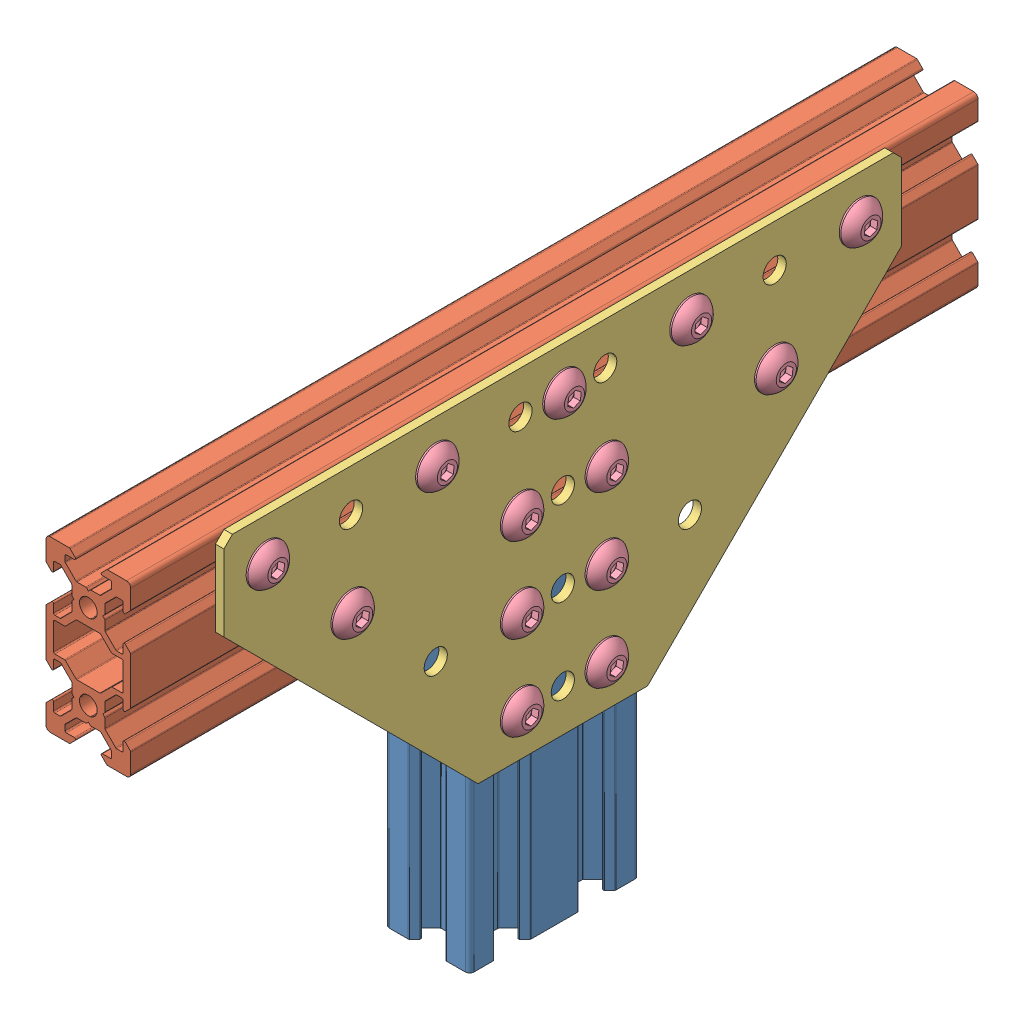
SolidWorks assembly Т-пластина 20 серия унив. 22отв  80х160х2 СБ, configuration По умолчанию. Lengths in mm.
Overall size (24.75 120 200).
16 component instances, 4 part files, 35 mates.
Components (placement in the parent):
- 204090-1: 204090 [По умолчанию] at (-10 0 -10) x (0 0 -1) z (0 1 0) size (40 20 80)
- 2040120-1: 2040120 [По умолчанию] at (-10 110 -120) x (0 -1 0) z (0 0 1) size (40 20 200)
- Т-пластина 20 серия унив. 22отв  80х160х2-1: Т-пластина 20 серия унив. 22отв  80х160х2 [По умолчанию] at (2 40 -20) x (0 0 -1) z (1 0 0) size (160 80 2)
- socket button head screw_iso-13: socket button head screw_iso [ISO 7380 - M5 x 10 - 10N] at (4.75 110 50) x (-1 0 0) z (0 0.924225 0.381849) size (12.75 9.5 9.5)
- socket button head screw_iso-14: socket button head screw_iso [ISO 7380 - M5 x 10 - 10N] at (4.75 90 30) x (-1 0 0) z (0 0.924225 0.381849) size (12.75 9.5 9.5)
- socket button head screw_iso-15: socket button head screw_iso [ISO 7380 - M5 x 10 - 10N] at (4.75 110 10) x (-1 0 0) z (0 0.924225 0.381849) size (12.75 9.5 9.5)
- socket button head screw_iso-16: socket button head screw_iso [ISO 7380 - M5 x 10 - 10N] at (4.75 110 -20) x (-1 0 0) z (0 0.924225 0.381849) size (12.75 9.5 9.5)
- socket button head screw_iso-17: socket button head screw_iso [ISO 7380 - M5 x 10 - 10N] at (4.75 110 -90) x (-1 0 0) z (0 0.924225 0.381849) size (12.75 9.5 9.5)
- socket button head screw_iso-18: socket button head screw_iso [ISO 7380 - M5 x 10 - 10N] at (4.75 110 -50) x (-1 0 0) z (0 0.924225 0.381849) size (12.75 9.5 9.5)
- socket button head screw_iso-19: socket button head screw_iso [ISO 7380 - M5 x 10 - 10N] at (4.75 90 -70) x (-1 0 0) z (0 0.924225 0.381849) size (12.75 9.5 9.5)
- socket button head screw_iso-20: socket button head screw_iso [ISO 7380 - M5 x 10 - 10N] at (4.75 90 -30) x (-1 0 0) z (0 0.924225 0.381849) size (12.75 9.5 9.5)
- socket button head screw_iso-21: socket button head screw_iso [ISO 7380 - M5 x 10 - 10N] at (4.75 90 -10) x (-1 0 0) z (0 0.924225 0.381849) size (12.75 9.5 9.5)
- socket button head screw_iso-22: socket button head screw_iso [ISO 7380 - M5 x 10 - 10N] at (4.75 50 -10) x (-1 0 0) z (0 0.924225 0.381849) size (12.75 9.5 9.5)
- socket button head screw_iso-23: socket button head screw_iso [ISO 7380 - M5 x 10 - 10N] at (4.75 70 -10) x (-1 0 0) z (0 0.924225 0.381849) size (12.75 9.5 9.5)
- socket button head screw_iso-24: socket button head screw_iso [ISO 7380 - M5 x 10 - 10N] at (4.75 70 -30) x (-1 0 0) z (0 0.924225 0.381849) size (12.75 9.5 9.5)
- socket button head screw_iso-25: socket button head screw_iso [ISO 7380 - M5 x 10 - 10N] at (4.75 50 -30) x (-1 0 0) z (0 0.924225 0.381849) size (12.75 9.5 9.5)
Mates (geometry in assembly coordinates):
- Совпадение1: coincident anti-aligned: plane of 204090-1 through (-10 0 -10) normal (0 -1 0)
- Совпадение2: coincident aligned: plane of 204090-1 through (0 80 -25.6) normal (1 0 0)
- Совпадение3: coincident aligned: plane of 204090-1 through (-20 80 0) normal (0 0 1)
- Совпадение4: coincident anti-aligned: plane of 204090-1 through (-10 80 -10) normal (0 1 0); plane of 2040120-1 through (-20 80 80) normal (0 -1 0)
- Совпадение5: coincident aligned: plane of 204090-1 through (0 80 -25.6) normal (1 0 0); plane of 2040120-1 through (0 80 80) normal (1 0 0)
- Совпадение6: coincident anti-aligned: plane of 2040120-1 through (0 94.4 80) normal (1 0 0); plane of Т-пластина 20 серия унив. 22отв  80х160х2-1 through (0 40 -20) normal (-1 0 0)
- Совпадение7: coincident aligned: plane of 2040120-1 through (0 120 80) normal (0 1 0); plane of Т-пластина 20 серия унив. 22отв  80х160х2-1 through (0 120 -20) normal (0 1 0)
- Расстояние1: distance = 20 mm aligned: plane of 2040120-1 through (-10 110 80) normal (0 0 1); plane of Т-пластина 20 серия унив. 22отв  80х160х2-1 through (0 120 60) normal (0 0 1)
- Совпадение9: coincident: plane of 204090-1 through (0 80 0) normal (0 0 1); line of Т-пластина 20 серия унив. 22отв  80х160х2-1 through (0 40 0) axis (1 0 0)
- Концентричный1: concentric aligned: cylinder of Т-пластина 20 серия унив. 22отв  80х160х2-1 through (2 110 50) axis (1 0 0) radius 2.75; cylinder of socket button head screw_iso-13 through (4.75 110 50) axis (1 0 0) radius 4.75
- Совпадение10: coincident anti-aligned: plane of Т-пластина 20 серия унив. 22отв  80х160х2-1 through (2 40 -20) normal (1 0 0); plane of socket button head screw_iso-13 through (2 109.0454 52.3106) normal (-1 0 0)
- Концентричный2: concentric aligned: cylinder of Т-пластина 20 серия унив. 22отв  80х160х2-1 through (2 90 30) axis (1 0 0) radius 2.75; cylinder of socket button head screw_iso-14 through (4.75 90 30) axis (1 0 0) radius 4.75
- Совпадение11: coincident anti-aligned: plane of Т-пластина 20 серия унив. 22отв  80х160х2-1 through (2 40 -20) normal (1 0 0); plane of socket button head screw_iso-14 through (2 89.0454 32.3106) normal (-1 0 0)
- Концентричный3: concentric aligned: cylinder of Т-пластина 20 серия унив. 22отв  80х160х2-1 through (2 110 10) axis (1 0 0) radius 2.75; cylinder of socket button head screw_iso-15 through (4.75 110 10) axis (1 0 0) radius 4.75
- Совпадение12: coincident anti-aligned: plane of Т-пластина 20 серия унив. 22отв  80х160х2-1 through (2 40 -20) normal (1 0 0); plane of socket button head screw_iso-15 through (2 109.0454 12.3106) normal (-1 0 0)
- Концентричный4: concentric anti-aligned: cylinder of Т-пластина 20 серия унив. 22отв  80х160х2-1 through (0 110 -20) axis (-1 0 0) radius 2.75; cylinder of socket button head screw_iso-16 through (4.75 110 -20) axis (1 0 0) radius 4.75
- Совпадение13: coincident anti-aligned: plane of Т-пластина 20 серия унив. 22отв  80х160х2-1 through (2 40 -20) normal (1 0 0); plane of socket button head screw_iso-16 through (2 109.0454 -17.6894) normal (-1 0 0)
- Концентричный5: concentric aligned: cylinder of Т-пластина 20 серия унив. 22отв  80х160х2-1 through (2 110 -90) axis (1 0 0) radius 2.75; cylinder of socket button head screw_iso-17 through (4.75 110 -90) axis (1 0 0) radius 4.75
- Совпадение14: coincident anti-aligned: plane of Т-пластина 20 серия унив. 22отв  80х160х2-1 through (2 40 -20) normal (1 0 0); plane of socket button head screw_iso-17 through (2 109.0454 -87.6894) normal (-1 0 0)
- Концентричный6: concentric aligned: cylinder of Т-пластина 20 серия унив. 22отв  80х160х2-1 through (2 110 -50) axis (1 0 0) radius 2.75; cylinder of socket button head screw_iso-18 through (4.75 110 -50) axis (1 0 0) radius 4.75
- Совпадение15: coincident anti-aligned: plane of Т-пластина 20 серия унив. 22отв  80х160х2-1 through (2 40 -20) normal (1 0 0); plane of socket button head screw_iso-18 through (2 109.0454 -47.6894) normal (-1 0 0)
- Концентричный7: concentric aligned: cylinder of Т-пластина 20 серия унив. 22отв  80х160х2-1 through (2 90 -70) axis (1 0 0) radius 2.75; cylinder of socket button head screw_iso-19 through (4.75 90 -70) axis (1 0 0) radius 4.75
- Совпадение16: coincident anti-aligned: plane of Т-пластина 20 серия унив. 22отв  80х160х2-1 through (2 40 -20) normal (1 0 0); plane of socket button head screw_iso-19 through (2 89.0454 -67.6894) normal (-1 0 0)
- Концентричный8: concentric aligned: cylinder of Т-пластина 20 серия унив. 22отв  80х160х2-1 through (2 90 -30) axis (1 0 0) radius 2.75; cylinder of socket button head screw_iso-20 through (4.75 90 -30) axis (1 0 0) radius 4.75
- Совпадение17: coincident anti-aligned: plane of Т-пластина 20 серия унив. 22отв  80х160х2-1 through (2 40 -20) normal (1 0 0); plane of socket button head screw_iso-20 through (2 89.0454 -27.6894) normal (-1 0 0)
- Концентричный9: concentric aligned: cylinder of Т-пластина 20 серия унив. 22отв  80х160х2-1 through (2 90 -10) axis (1 0 0) radius 2.75; cylinder of socket button head screw_iso-21 through (4.75 90 -10) axis (1 0 0) radius 4.75
- Совпадение18: coincident anti-aligned: plane of Т-пластина 20 серия унив. 22отв  80х160х2-1 through (2 40 -20) normal (1 0 0); plane of socket button head screw_iso-21 through (2 89.0454 -7.6894) normal (-1 0 0)
- Концентричный10: concentric aligned: cylinder of Т-пластина 20 серия унив. 22отв  80х160х2-1 through (2 50 -10) axis (1 0 0) radius 2.75; cylinder of socket button head screw_iso-22 through (4.75 50 -10) axis (1 0 0) radius 4.75
- Совпадение19: coincident anti-aligned: plane of Т-пластина 20 серия унив. 22отв  80х160х2-1 through (2 40 -20) normal (1 0 0); plane of socket button head screw_iso-22 through (2 49.0454 -7.6894) normal (-1 0 0)
- Концентричный11: concentric aligned: cylinder of Т-пластина 20 серия унив. 22отв  80х160х2-1 through (2 70 -10) axis (1 0 0) radius 2.75; cylinder of socket button head screw_iso-23 through (4.75 70 -10) axis (1 0 0) radius 4.75
- Совпадение20: coincident anti-aligned: plane of Т-пластина 20 серия унив. 22отв  80х160х2-1 through (2 40 -20) normal (1 0 0); plane of socket button head screw_iso-23 through (2 69.0454 -7.6894) normal (-1 0 0)
- Концентричный12: concentric aligned: cylinder of Т-пластина 20 серия унив. 22отв  80х160х2-1 through (2 70 -30) axis (1 0 0) radius 2.75; cylinder of socket button head screw_iso-24 through (4.75 70 -30) axis (1 0 0) radius 4.75
- Совпадение21: coincident anti-aligned: plane of Т-пластина 20 серия унив. 22отв  80х160х2-1 through (2 40 -20) normal (1 0 0); plane of socket button head screw_iso-24 through (2 69.0454 -27.6894) normal (-1 0 0)
- Концентричный13: concentric aligned: cylinder of Т-пластина 20 серия унив. 22отв  80х160х2-1 through (2 50 -30) axis (1 0 0) radius 2.75; cylinder of socket button head screw_iso-25 through (4.75 50 -30) axis (1 0 0) radius 4.75
- Совпадение22: coincident anti-aligned: plane of Т-пластина 20 серия унив. 22отв  80х160х2-1 through (2 40 -20) normal (1 0 0); plane of socket button head screw_iso-25 through (2 49.0454 -27.6894) normal (-1 0 0)
